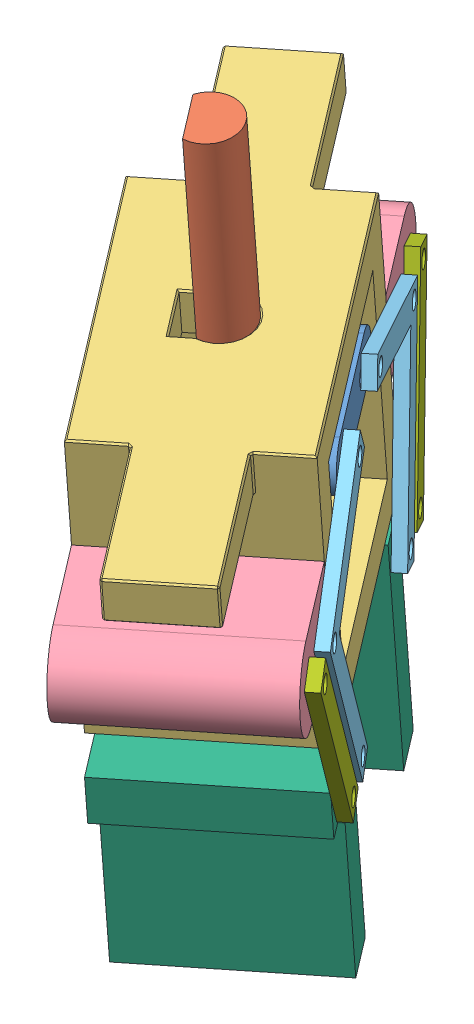
SolidWorks assembly [SPCN] Assembly, configuration Default. Lengths in mm.
Overall size (621.35 899.88 752).
11 component instances, 7 part files, 20 mates.
Components (placement in the parent):
- [SPCN] Ring-Situated Pad-1: [SPCN] Ring-Situated Pad [Default] at (-2022.5807 1224.0452 -595.7978) x (0.585102 -0.118835 0.802206) z (0.809831 0.033456 -0.585708) size (200 60 156.78)
- [SPCN] Actuator Rod-2: [SPCN] Actuator Rod [Default] at (-2023.436 1204.1982 -598.1141) x (0.664115 -0.114835 0.738759) z (0.042764 0.99235 0.115811) size (70 55.97 350)
- [SPCN] Gripper Housing & Interface-1: [SPCN] Gripper Housing & Interface [Default] at (-2095.6678 1028.7513 -571.4203) x (-0.585102 0.118835 -0.802206) z (0.809831 0.033456 -0.585708) size (720 350 228.57)
- [SPCN] Interface and Pin Linker (Right)-1: [SPCN] Interface and Pin Linker (Right) [Default] at (-2206.7824 1198.6178 -715.3505) x (0.585102 -0.118835 0.802206) z (0.809831 0.033456 -0.585708) size (157.14 100 228.57)
- [SPCN] Interface and Pin Linker (Right)-2: [SPCN] Interface and Pin Linker (Right) [Default] at (-1842.3951 1156.2798 -487.1212) x (-0.585102 0.118835 -0.802206) z (-0.809831 -0.033456 0.585708) size (157.14 100 228.57)
- [SPCN] Gripper Lever-4: [SPCN] Gripper Lever [Default] at (-2081.542 1185.9258 -874.6222) x (-0.555664 -0.276497 -0.784084) z (0.809831 0.033456 -0.585708) size (220 270 15)
- [SPCN] Gripper Lever-5: [SPCN] Gripper Lever [Default] at (-1772.5805 1126.1445 -476.4603) x (0.522398 -0.495451 0.693995) z (-0.809831 -0.033456 0.585708) size (220 270 15)
- [SPCN] Finger-1: [SPCN] Finger [Default] at (-2007.0366 972.2769 -783.8106) x (0.585102 -0.118835 0.802206) z (-0.809831 -0.033456 0.585708) size (110 270 222.57)
- [SPCN] Finger-2: [SPCN] Finger [Default] at (-2056.4387 938.2567 -474.0584) x (-0.585102 0.118835 -0.802206) z (0.809831 0.033456 -0.585708) size (110 270 222.57)
- [SPCN] Linkage-3: [SPCN] Linkage [Default] at (-2043.4663 942.8223 -835.8627) x (0.555664 0.276497 0.784084) z (0.809831 0.033456 -0.585708) size (35 270 15)
- [SPCN] Linkage-4: [SPCN] Linkage [Default] at (-1824.6297 884.7492 -536.6048) x (0.522398 -0.495451 0.693995) z (0.809831 0.033456 -0.585708) size (35 270 15)
Mates (geometry in assembly coordinates):
- Concentric1: concentric anti-aligned: cylinder of [SPCN] Gripper Housing & Interface-1 through (-2020.74 1266.7603 -590.8128) axis (0.042764 0.99235 0.115811) radius 35; cylinder of [SPCN] Actuator Rod-2 through (-2008.4686 1551.5208 -557.5803) axis (-0.042764 -0.99235 -0.115811) radius 35
- Parallel1: parallel aligned: plane of [SPCN] Ring-Situated Pad-1 through (-1889.4997 1209.6268 -607.7392) normal (0.809831 0.033456 -0.585708); plane of [SPCN] Gripper Housing & Interface-1 through (-1941.0171 972.8788 -692.4942) normal (0.809831 0.033456 -0.585708)
- Coincident2: coincident anti-aligned: circle of [SPCN] Gripper Housing & Interface-1; circle of [SPCN] Interface and Pin Linker (Right)-1
- Coincident6: coincident anti-aligned: circle of [SPCN] Gripper Housing & Interface-1; circle of [SPCN] Interface and Pin Linker (Right)-1
- Concentric5: concentric anti-aligned: circle of [SPCN] Ring-Situated Pad-1; circle of [SPCN] Actuator Rod-2
- Coincident9: coincident aligned: plane of [SPCN] Ring-Situated Pad-1 through (-2023.436 1204.1982 -598.1141) normal (-0.042764 -0.99235 -0.115811); plane of [SPCN] Actuator Rod-2 through (-2023.436 1204.1982 -598.1141) normal (-0.042764 -0.99235 -0.115811)
- Coincident10: coincident aligned: circle of [SPCN] Gripper Housing & Interface-1; circle of [SPCN] Interface and Pin Linker (Right)-2
- Coincident11: coincident aligned: circle of [SPCN] Gripper Housing & Interface-1; circle of [SPCN] Interface and Pin Linker (Right)-2
- Tangent7: tangent anti-aligned: plane of [SPCN] Ring-Situated Pad-1 through (-1957.2141 1213.3693 -701.151) normal (0.042764 0.99235 0.115811); cylinder of [SPCN] Gripper Lever-4 through (-1953.5795 1225.6106 -721.0377) axis (0.809831 0.033456 -0.585708) radius 10
- Coincident16: coincident anti-aligned: circle of [SPCN] Interface and Pin Linker (Right)-1; circle of [SPCN] Gripper Lever-4
- Coincident17: coincident anti-aligned: circle of [SPCN] Interface and Pin Linker (Right)-2; circle of [SPCN] Gripper Lever-5
- Tangent8: tangent anti-aligned: plane of [SPCN] Ring-Situated Pad-1 through (-1904.5549 1202.6742 -628.9525) normal (0.042764 0.99235 0.115811); cylinder of [SPCN] Gripper Lever-5 through (-1895.1855 1210.7817 -615.536) axis (-0.809831 -0.033456 0.585708) radius 10
- Coincident22: coincident anti-aligned: circle of [SPCN] Gripper Lever-4; circle of [SPCN] Finger-1
- Concentric9: concentric anti-aligned: circle of [SPCN] Gripper Lever-5; circle of [SPCN] Finger-2
- Coincident26: coincident anti-aligned: circle of [SPCN] Interface and Pin Linker (Right)-1; circle of [SPCN] Linkage-3
- Concentric8: concentric anti-aligned: circle of [SPCN] Finger-1; circle of [SPCN] Linkage-3
- Concentric11: concentric aligned: circle of [SPCN] Interface and Pin Linker (Right)-2; circle of [SPCN] Linkage-4
- Coincident32: coincident aligned: circle of [SPCN] Finger-2; circle of [SPCN] Linkage-4
- Coincident33: coincident anti-aligned: circle of [SPCN] Gripper Lever-5; circle of [SPCN] Finger-2
- Parallel2: parallel anti-aligned: plane of [SPCN] Actuator Rod-2 through (-2005.515 1547.3527 -522.9551) normal (-0.809831 -0.033456 0.585708); plane of [SPCN] Gripper Housing & Interface-1 through (-2038.0321 1261.7558 -541.545) normal (0.809831 0.033456 -0.585708)
